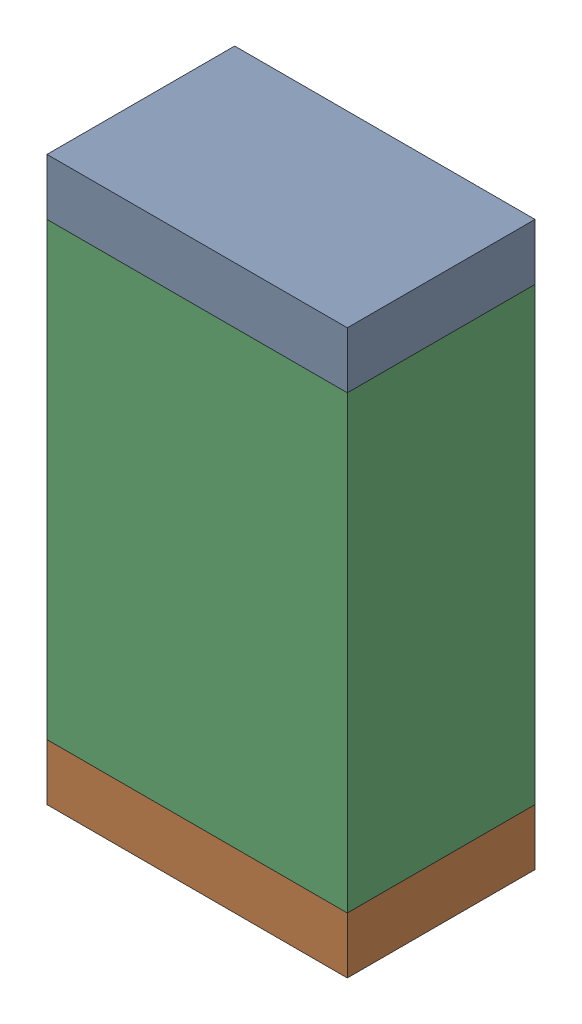
SolidWorks assembly R30, configuration Default. Lengths in mm.
Overall size (0.8 1.5 0.5).
6 component instances, 2 part files, 0 mates.
Components (placement in the parent):
- 810156592-1: 810156592 [Default] at (119.45 48.875 0) size (0.8 0.15 0.5)
  - Extruded_7-1: Extruded_7 [Default] at origin size (0.8 0.15 0.5)
- 810156592-2: 810156592 [Default] at (119.45 47.525 0) size (0.8 0.15 0.5)
  - Extruded_7-1: Extruded_7 [Default] at origin size (0.8 0.15 0.5)
- 810156976-1: 810156976 [Default] at (119.45 48.2 0) size (0.8 1.2 0.5)
  - Extruded_6-1: Extruded_6 [Default] at origin size (0.8 1.2 0.5)
